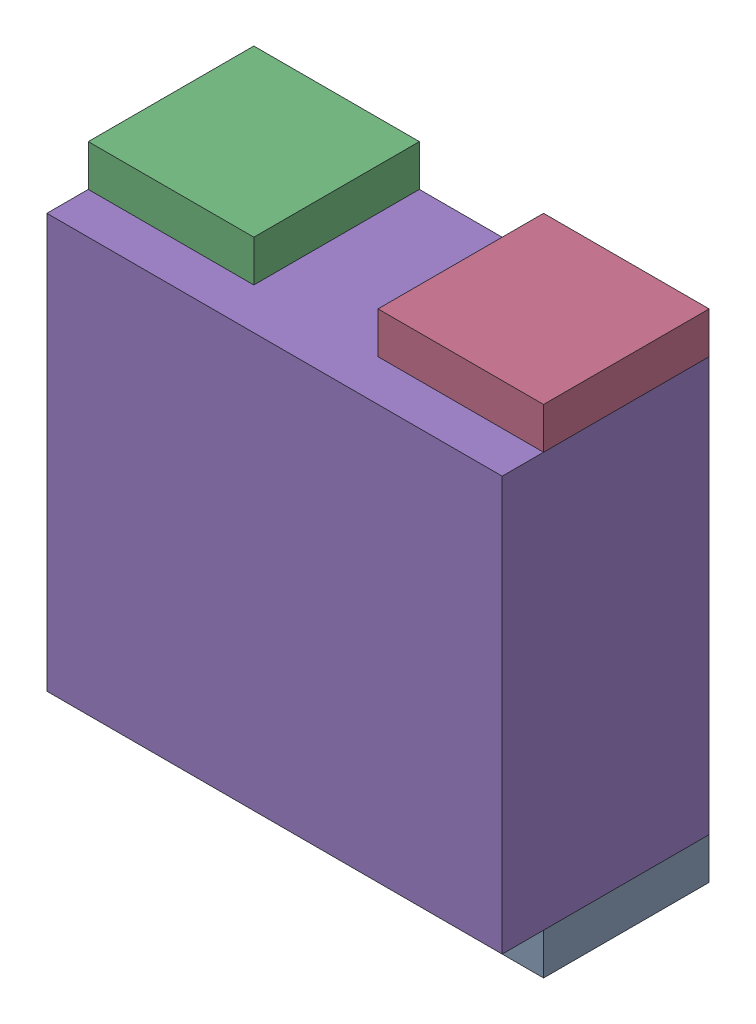
SolidWorks assembly RN14, configuration Default. Lengths in mm.
Overall size (1.1 1.2 0.5).
10 component instances, 2 part files, 0 mates.
Components (placement in the parent):
- 810157616-1: 810157616 [Default] at (116 60.5 0) size (0.4 0.1 0.4)
  - Extruded_12-1: Extruded_12 [Default] at origin size (0.4 0.1 0.4)
- 810157616-2: 810157616 [Default] at (115.3 60.5 0) size (0.4 0.1 0.4)
  - Extruded_12-1: Extruded_12 [Default] at origin size (0.4 0.1 0.4)
- 810157616-3: 810157616 [Default] at (115.3 61.6 0) size (0.4 0.1 0.4)
  - Extruded_12-1: Extruded_12 [Default] at origin size (0.4 0.1 0.4)
- 810157616-4: 810157616 [Default] at (116 61.6 0) size (0.4 0.1 0.4)
  - Extruded_12-1: Extruded_12 [Default] at origin size (0.4 0.1 0.4)
- 810156720-1: 810156720 [Default] at (115.65 61.05 0) size (1.1 1 0.5)
  - Extruded_13-1: Extruded_13 [Default] at origin size (1.1 1 0.5)
